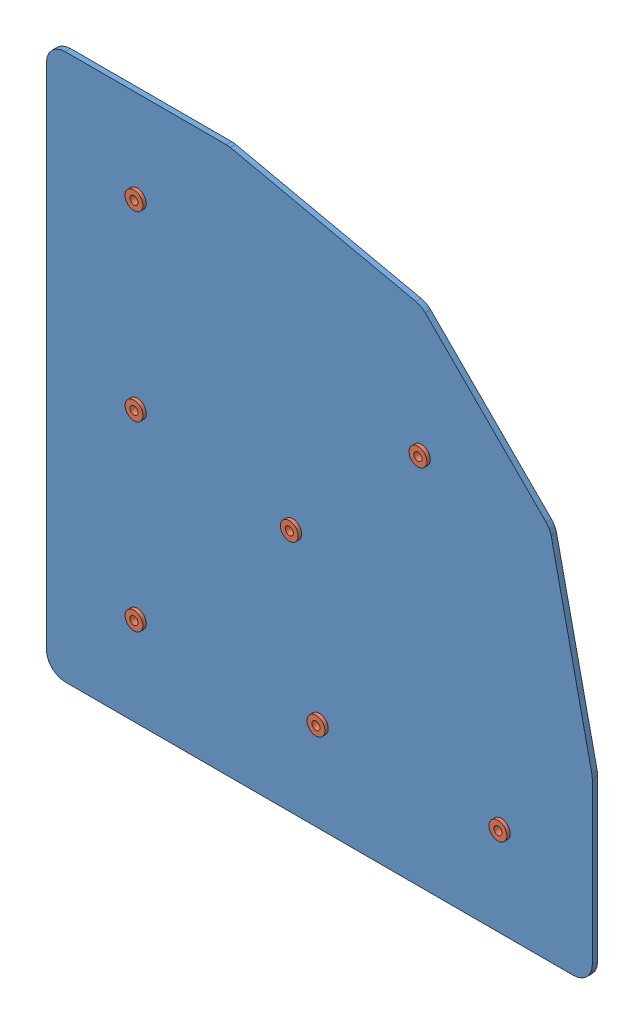
SolidWorks assembly corner_45_w_rivets170927, configuration Default. Lengths in mm.
Overall size (161.92 161.93 7).
8 component instances, 2 part files, 14 mates.
Components (placement in the parent):
- 2inch_90degCorner_45170927-1: 2inch_90degCorner_45170927 [Default] at (-27.7555 -48.0351 3.7368) size (161.93 161.93 1.59)
- 0.3125 rivet170927-1: 0.3125 rivet170927 [Default] at (-0.768 32.9274 5.3243) x (1 0 0) z (0 -1 0) size (5.3 7 5.3)
- 0.3125 rivet170927-2: 0.3125 rivet170927 [Default] at (-0.768 86.9024 5.3243) x (0.987351 0.158553 0) z (0.158553 -0.987351 0) size (5.3 7 5.3)
- 0.3125 rivet170927-3: 0.3125 rivet170927 [Default] at (-0.768 -21.0476 5.3243) x (0.959125 0.282984 0) z (0.282984 -0.959125 0) size (5.3 7 5.3)
- 0.3125 rivet170927-4: 0.3125 rivet170927 [Default] at (45.3025 25.023 5.3243) x (0.928571 0.371154 0) z (0.371154 -0.928571 0) size (5.3 7 5.3)
- 0.3125 rivet170927-5: 0.3125 rivet170927 [Default] at (53.207 -21.0476 5.3243) x (0.906989 0.421154 0) z (0.421154 -0.906989 0) size (5.3 7 5.3)
- 0.3125 rivet170927-6: 0.3125 rivet170927 [Default] at (107.182 -21.0476 5.3243) x (0.902849 0.429957 0) z (0.429957 -0.902849 0) size (5.3 7 5.3)
- 0.3125 rivet170927-7: 0.3125 rivet170927 [Default] at (83.4686 63.1891 5.3243) x (0.919615 0.39282 0) z (0.39282 -0.919615 0) size (5.3 7 5.3)
Mates (geometry in assembly coordinates):
- Coincident1: coincident anti-aligned: plane of 2inch_90degCorner_45170927-1 through (128.6132 -42.4788 5.3243) normal (0 0 1); plane of 0.3125 rivet170927-1 through (-2.418 32.9274 5.3243) normal (0 0 -1)
- Concentric1: concentric anti-aligned: circle of 2inch_90degCorner_45170927-1; circle of 0.3125 rivet170927-1
- Coincident2: coincident anti-aligned: plane of 2inch_90degCorner_45170927-1 through (128.6132 -42.4788 5.3243) normal (0 0 1); plane of 0.3125 rivet170927-2 through (-2.3972 86.6408 5.3243) normal (0 0 -1)
- Concentric2: concentric anti-aligned: circle of 2inch_90degCorner_45170927-1; circle of 0.3125 rivet170927-2
- Coincident3: coincident anti-aligned: plane of 2inch_90degCorner_45170927-1 through (128.6132 -42.4788 5.3243) normal (0 0 1); plane of 0.3125 rivet170927-3 through (-2.3506 -21.5145 5.3243) normal (0 0 -1)
- Concentric3: concentric anti-aligned: circle of 2inch_90degCorner_45170927-1; circle of 0.3125 rivet170927-3
- Coincident4: coincident anti-aligned: plane of 2inch_90degCorner_45170927-1 through (128.6132 -42.4788 5.3243) normal (0 0 1); plane of 0.3125 rivet170927-4 through (43.7704 24.4106 5.3243) normal (0 0 -1)
- Concentric4: concentric anti-aligned: circle of 2inch_90degCorner_45170927-1; circle of 0.3125 rivet170927-4
- Coincident5: coincident anti-aligned: plane of 2inch_90degCorner_45170927-1 through (128.6132 -42.4788 5.3243) normal (0 0 1); plane of 0.3125 rivet170927-5 through (51.7104 -21.7425 5.3243) normal (0 0 -1)
- Concentric5: concentric anti-aligned: circle of 2inch_90degCorner_45170927-1; circle of 0.3125 rivet170927-5
- Coincident6: coincident anti-aligned: plane of 2inch_90degCorner_45170927-1 through (128.6132 -42.4788 5.3243) normal (0 0 1); plane of 0.3125 rivet170927-6 through (105.6923 -21.757 5.3243) normal (0 0 -1)
- Concentric6: concentric anti-aligned: circle of 2inch_90degCorner_45170927-1; circle of 0.3125 rivet170927-6
- Coincident7: coincident anti-aligned: plane of 2inch_90degCorner_45170927-1 through (128.6132 -42.4788 5.3243) normal (0 0 1); plane of 0.3125 rivet170927-7 through (81.9512 62.5409 5.3243) normal (0 0 -1)
- Concentric7: concentric anti-aligned: circle of 2inch_90degCorner_45170927-1; circle of 0.3125 rivet170927-7
